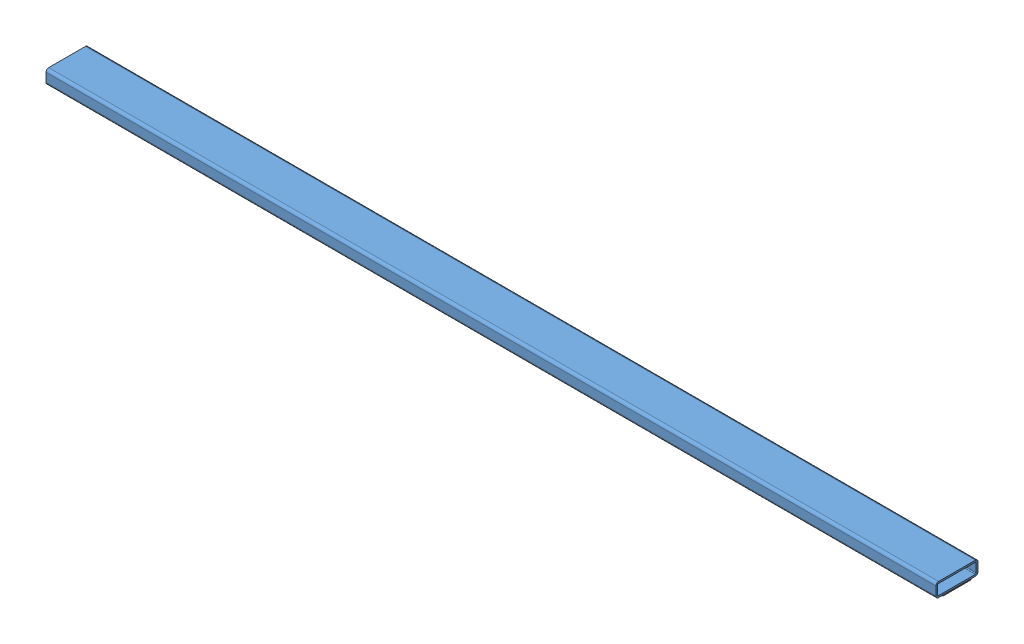
SolidWorks assembly GE-20047, configuration Default. Lengths in mm.
Overall size (1612.9 26.99 76.2).
2 component instances, 2 part files, 6 mates.
Components (placement in the parent):
- GE-20052-1: GE-20052 [Default] at origin size (1612.9 25.4 76.2)
- Hook_2_63-50-1: Hook_2_63-50 [Default] at (-806.45 -1.5875 25.4) size (1612.9 1.59 50.8)
Mates (geometry in assembly coordinates):
- Coincident2: coincident: plane of GE-20052-1 through (806.45 20.6248 -33.3248) normal (1 0 0); plane of Hook_2_63-50-1 through (806.45 26.9875 25.4) normal (1 0 0)
- Width1: width: plane of Hook_2_63-50-1 through (-806.45 26.9875 25.4) normal (0 0 1); plane of GE-20052-1 through (-806.45 26.9875 -25.4) normal (0 0 -1); plane of Hook_2_63-50-1 through (806.45 20.6248 -38.1) normal (0 0 -1); plane of GE-20052-1 through (806.45 20.6248 38.1) normal (0 0 1)
- Coincident3: coincident aligned: plane of GE-20052-1 through (0 0 0) normal (0 0 1)
- Coincident4: coincident aligned: plane of GE-20052-1 through (0 0 0) normal (0 1 0)
- Coincident5: coincident aligned: plane of GE-20052-1 through (0 0 0) normal (1 0 0)
- Coincident6: coincident anti-aligned: plane of GE-20052-1 through (806.45 0 -33.3248) normal (0 -1 0); plane of Hook_2_63-50-1 through (-806.45 0 25.4) normal (0 1 0)
